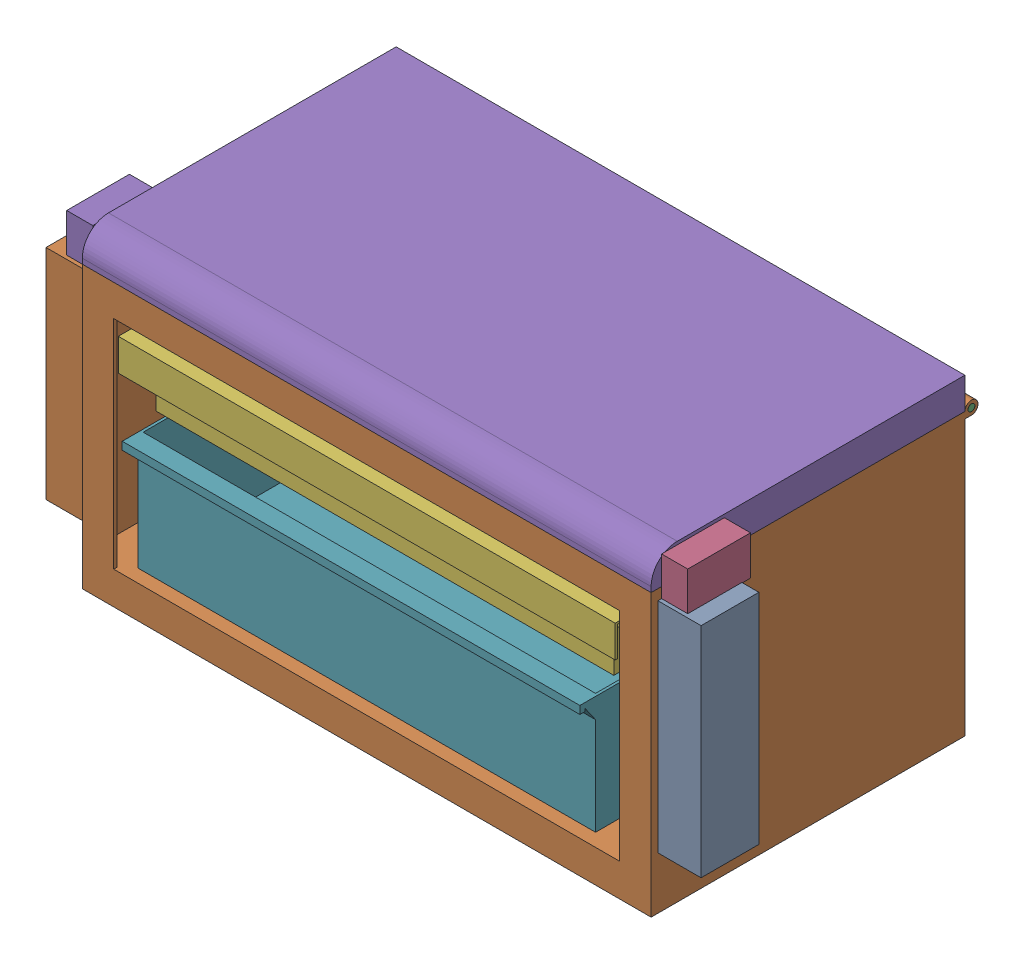
SolidWorks assembly SP-A0101-AD-Tool Box, configuration Default. Lengths in mm.
Overall size (318.13 151.77 166.37).
6 component instances, 6 part files, 19 mates.
Components (placement in the parent):
- SP-00001-AD-Box-1: SP-00001-AD-Box [Default] at (1.524 136.525 150.876) size (318.13 139.7 158.75)
- SP-00005-AA-Hinge Pin-2: SP-00005-AA-Hinge Pin [Default] at (276.225 136.525 -3.175) x (-1 0 0) z (0 0.655217 -0.75544) size (276.23 3.3 3.3)
- SP-00002-AB-Lid-3: SP-00002-AB-Lid [Default] at (1.524 136.525 150.876) size (301.63 20.57 158.75)
- SP-00003-AA-Upper Drawer-2: SP-00003-AA-Upper Drawer [Default] at (138.1125 83.7565 143.51) size (241.3 31.18 135.89)
- SP-00004-AA-lower drawer-2: SP-00004-AA-lower drawer [Default] at (138.1125 22.225 88.9) size (222.25 57.15 134.62)
- SP-00010-AD-Top Insert-1: SP-00010-AD-Top Insert [Default] at (1.524 122.809 150.876) size (273.6 12.7 147.51)
Mates (geometry in assembly coordinates):
- Concentric3: concentric aligned: cylinder of SP-00001-AD-Box-1 through (193.675 136.525 -3.175) axis (1 0 0) radius 1.651; cylinder of SP-00005-AA-Hinge Pin-2 through (0 136.525 -3.175) axis (1 0 0) radius 1.651
- Concentric4: concentric anti-aligned: cylinder of SP-00001-AD-Box-1 through (82.55 136.525 -3.175) axis (-1 0 0) radius 1.651; cylinder of SP-00005-AA-Hinge Pin-2 through (0 136.525 -3.175) axis (1 0 0) radius 1.651
- Coincident8: coincident aligned: plane of SP-00001-AD-Box-1 through (276.225 0 152.4) normal (1 0 0); plane of SP-00005-AA-Hinge Pin-2 through (276.225 136.525 -3.175) normal (1 0 0)
- Coincident10: coincident aligned: plane of SP-00001-AD-Box-1 through (276.225 0 152.4) normal (1 0 0); plane of SP-00002-AB-Lid-3 through (276.225 151.765 150.876) normal (1 0 0)
- Concentric6: concentric anti-aligned: cylinder of SP-00005-AA-Hinge Pin-2 through (0 136.525 -3.175) axis (1 0 0) radius 1.651; cylinder of SP-00002-AB-Lid-3 through (188.9125 136.525 -3.175) axis (-1 0 0) radius 1.651
- Coincident13: coincident anti-aligned: plane of SP-00001-AD-Box-1 through (249.2375 102.235 184.2008) normal (-1 0 0); plane of SP-00003-AA-Upper Drawer-2 through (249.2375 86.2965 143.51) normal (1 0 0)
- Distance5: distance = 6.35 mm anti-aligned: plane of SP-00001-AD-Box-1 through (1.524 121.285 150.876) normal (0 -1 0); plane of SP-00003-AA-Upper Drawer-2 through (17.4625 114.935 143.51) normal (0 1 0)
- LimitDistance3: limit distance = 0 mm aligned: plane of SP-00003-AA-Upper Drawer-2 through (17.4625 114.935 152.4) normal (0 0 1); plane of SP-00001-AD-Box-1 through (0 0 152.4) normal (0 0 1)
- Coincident14: coincident anti-aligned: plane of SP-00001-AD-Box-1 through (249.2375 51.435 184.2008) normal (-1 0 0); plane of SP-00004-AA-lower drawer-2 through (249.2375 79.375 152.4) normal (1 0 0)
- Distance6: distance = 6.35 mm anti-aligned: plane of SP-00001-AD-Box-1 through (1.524 15.875 150.876) normal (0 1 0); plane of SP-00004-AA-lower drawer-2 through (138.1125 22.225 88.9) normal (0 -1 0)
- LimitDistance4: limit distance = 0 mm aligned: plane of SP-00001-AD-Box-1 through (0 0 152.4) normal (0 0 1); plane of SP-00004-AA-lower drawer-2 through (249.2375 79.375 152.4) normal (0 0 1)
- Coincident15: coincident: point of SP-00001-AD-Box-1
- Parallel1: parallel aligned: plane of SP-00001-AD-Box-1 through (1.524 136.525 150.876) normal (0 1 0)
- Parallel2: parallel aligned: plane of SP-00001-AD-Box-1 through (1.524 136.525 150.876) normal (1 0 0)
- Parallel3: parallel aligned: plane of SP-00001-AD-Box-1 through (1.524 136.525 150.876) normal (0 0 1)
- LimitAngle1: limit planar angle = 0 rad anti-aligned: plane of SP-00002-AB-Lid-3 through (1.524 136.525 150.876) normal (0 -1 0); plane of SP-00001-AD-Box-1 through (1.524 136.525 150.876) normal (0 1 0)
- Coincident17: coincident anti-aligned: plane of SP-00001-AD-Box-1 through (1.524 -312.0725 150.876) normal (1 0 0); plane of SP-00010-AD-Top Insert-1 through (1.524 124.333 150.876) normal (-1 0 0)
- Coincident18: coincident anti-aligned: plane of SP-00001-AD-Box-1 through (1.524 122.809 150.876) normal (0 1 0); plane of SP-00010-AD-Top Insert-1 through (1.524 122.809 150.876) normal (0 -1 0)
- Coincident19: coincident anti-aligned: plane of SP-00001-AD-Box-1 through (1.524 -312.0725 150.876) normal (0 0 -1); plane of SP-00010-AD-Top Insert-1 through (1.524 124.333 150.876) normal (0 0 1)
